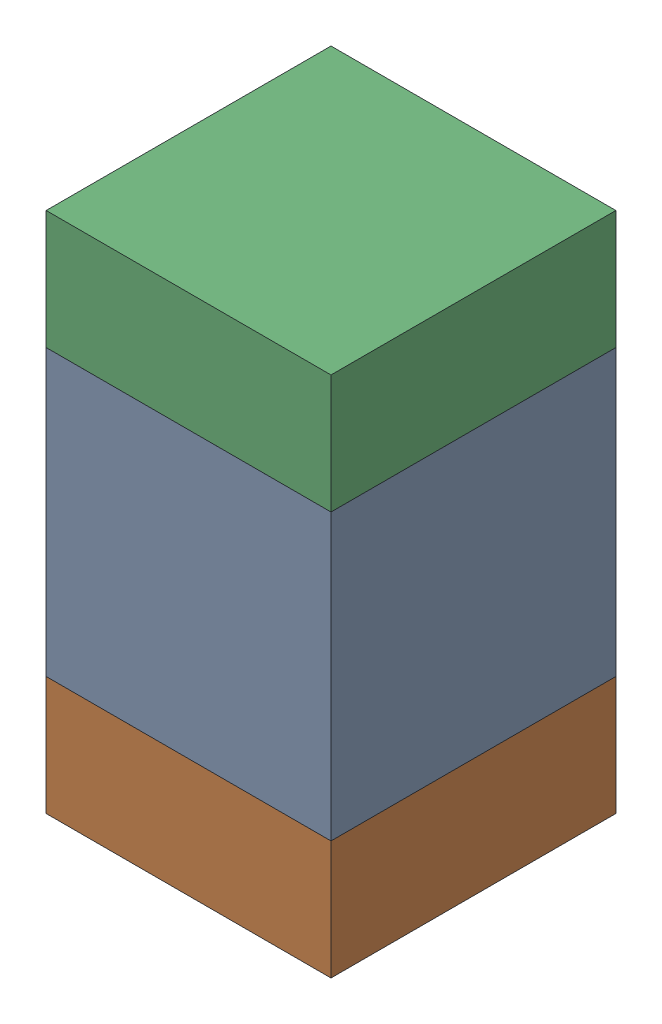
SolidWorks assembly C313_2PCB, configuration Default. Lengths in mm.
Overall size (0.6 1.1 0.6).
6 component instances, 2 part files, 0 mates.
Components (placement in the parent):
- 761606048-1: 761606048 [Default] at (133.4 95.6 -2.2638) size (0.6 0.6 0.6)
  - Extruded_9-1: Extruded_9 [Default] at origin size (0.6 0.6 0.6)
- 854785296-1: 854785296 [Default] at (133.4 95.175 -2.2638) size (0.6 0.25 0.6)
  - Extruded_10-1: Extruded_10 [Default] at origin size (0.6 0.25 0.6)
- 854785296-2: 854785296 [Default] at (133.4 96.025 -2.2638) size (0.6 0.25 0.6)
  - Extruded_10-1: Extruded_10 [Default] at origin size (0.6 0.25 0.6)
